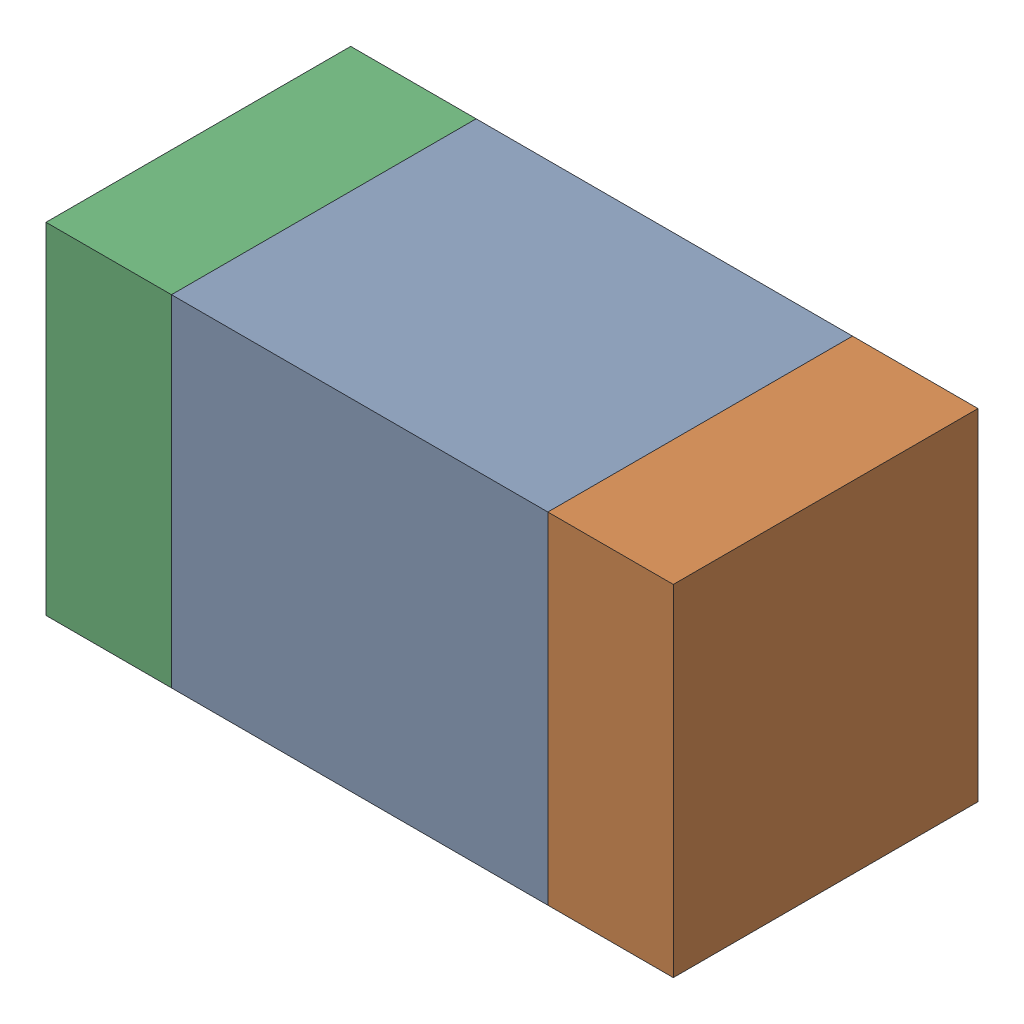
SolidWorks assembly C10, configuration 默认. Lengths in mm.
Overall size (1.75 0.95 0.85).
6 component instances, 2 part files, 0 mates.
Components (placement in the parent):
- 6241789056-1: 6241789056 [默认] at (32.639 15.494 -2.5414) size (1.05 0.95 0.85)
  - Extruded-4-1: Extruded-4 [默认] at origin size (1.05 0.95 0.85)
- 6241789456-1: 6241789456 [默认] at (33.339 15.494 -2.5414) size (0.35 0.95 0.85)
  - Extruded-5-1: Extruded-5 [默认] at origin size (0.35 0.95 0.85)
- 6241789456-2: 6241789456 [默认] at (31.939 15.494 -2.5414) size (0.35 0.95 0.85)
  - Extruded-5-1: Extruded-5 [默认] at origin size (0.35 0.95 0.85)
